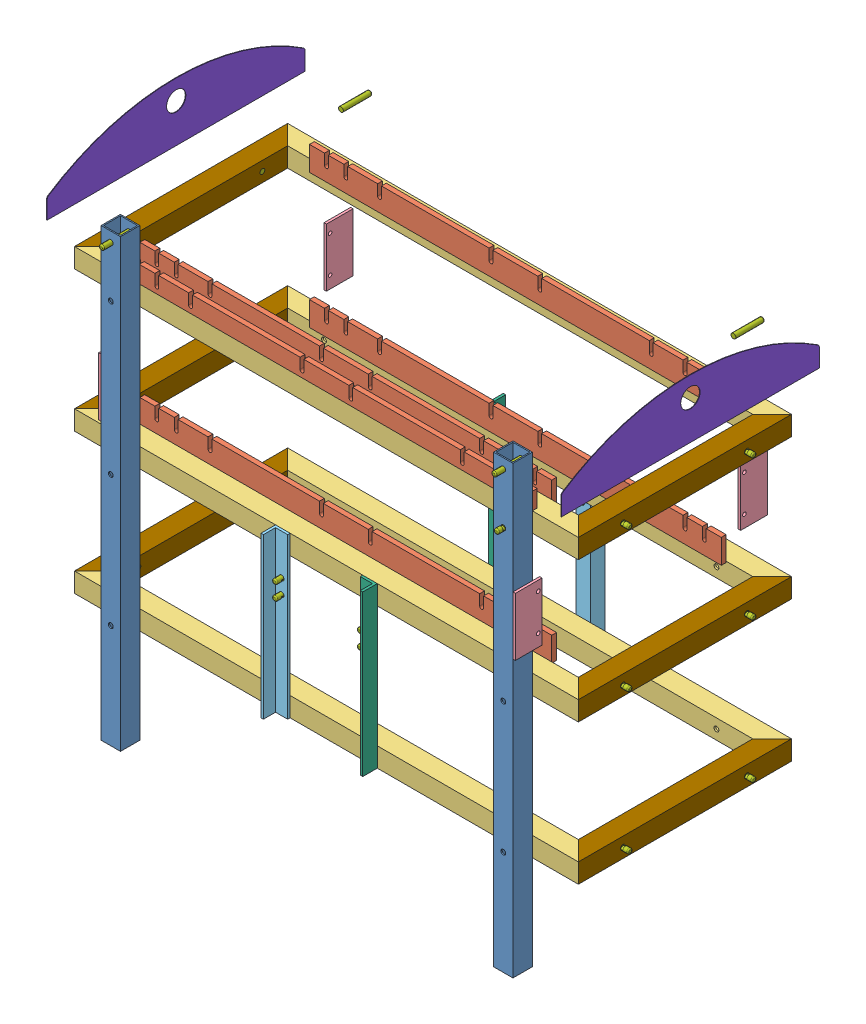
SolidWorks assembly 300-TableCage, configuration Default. Lengths in mm.
Overall size (1358.9 1271.5 704.85).
59 component instances, 12 part files, 76 mates.
Components (placement in the parent):
- 305-LegMain-1: 305-LegMain [Default] x (-1 0 0) z (0 1 0) size (50.8 50.8 1168.4)
- 307-HoldingBarRods-1: 307-HoldingBarRods [Default] at (0 0 279.4) x (-1 0 0) z (0 0 -1) size (1079.5 63.5 12.7)
- 309-TubingSquareTop-1: 309-TubingSquareTop [Default] x (0 0 -1) z (1 0 0) size (50.8 50.8 1320.8)
- 309-TubingSquareTop-2: 309-TubingSquareTop [Default] at (0 -368.3 0) x (0 0 -1) z (1 0 0) size (50.8 50.8 1320.8)
- 311-PlateYoke-1: 311-PlateYoke [Default] at (539.75 0 0) x (0 1 0) z (1 0 0) size (152.4 69.85 6.35)
- 309-TubingSquareTop-3: 309-TubingSquareTop [Default] at (0 -736.6 0) x (0 0 -1) z (1 0 0) size (50.8 50.8 1320.8)
- 308-AngleBracket-1: 308-AngleBracket [Default] at (851.05 400.05 9.525) x (0 0 -1) z (0 1 0) size (38.1 38.1 419.1)
- 308-AngleBracketMirror-1: 308-AngleBracketMirror [Default] at (-851.05 400.05 9.525) x (0 0 1) z (0 1 0) size (38.1 38.1 419.1)
- 321-DowellGrooved-1: 321-DowellGrooved [Default] at (851.05 400.05 279.4) x (0 -1 0) z (0 0 -1) size (12.7 12.7 25.4)
- 321-DowellGrooved-2: 321-DowellGrooved [Default] at (1073.3 400.05 279.4) x (0 -1 0) z (0 0 -1) size (12.7 12.7 25.4)
- 321-DowellGrooved-3: 321-DowellGrooved [Default] at (851.05 361.95 279.4) x (0 -1 0) z (0 0 -1) size (12.7 12.7 25.4)
- 321-DowellGrooved-4: 321-DowellGrooved [Default] at (1073.3 361.95 279.4) x (0 -1 0) z (0 0 -1) size (12.7 12.7 25.4)
- 400-LidUpper-1: 400-LidUpper [Default] at origin size (1349.2 153.62 676.1)
  - 401-Dome-1: 401-Dome [Default] x (0 0 -1) z (1 0 0) size (676.1 153.62 1346.2) (hidden)
  - 402-SideWall-1: 402-SideWall [Default] at (673.1 37.11 0) x (0 0 -1) z (1 0 0) size (676.1 153.62 1.5)
  - 402-SideWall-2: 402-SideWall [Default] at (-674.6 37.11 0) x (0 0 -1) z (1 0 0) size (676.1 153.62 1.5)
- 330-LexanSideShield-1: 330-LexanSideShield [Default] at (0 0 330.2) size (1330.33 882.65 4.76) (hidden)
- 304-BarUpper-1: 304-BarUpper [Default] at (-457.2 1473.2 -91.6) x (0 -1 0) z (0 0 1) size (50.8 50.8 558.8)
- 304-BarUpper-2: 304-BarUpper [Default] at (-457.2 1104.9 -91.6) x (0 -1 0) z (0 0 1) size (50.8 50.8 558.8)
- 304-BarUpper-3: 304-BarUpper [Default] at (-457.2 736.6 -91.6) x (0 -1 0) z (0 0 1) size (50.8 50.8 558.8)
- 321-DowellGrooved-5: 321-DowellGrooved [plain-long] at (-447.825 1202.1089 330.2) x (0 1 0) z (0 0 -1) size (12.7 12.7 76.2)
- 321-DowellGrooved-8: 321-DowellGrooved [long] at (654.05 1068.7589 1124.575) x (0 1 0) z (-1 0 0) size (12.7 12.7 69.85)
- 321-DowellGrooved-11: 321-DowellGrooved [long] at (654.05 1068.7589 799.775) x (0 1 0) z (-1 0 0) size (12.7 12.7 69.85)
- 321-DowellGrooved-13: 321-DowellGrooved [long] at (654.05 332.1589 799.775) x (0 1 0) z (-1 0 0) size (12.7 12.7 69.85)
- 321-DowellGrooved-10: 321-DowellGrooved [long] at (654.05 332.1589 1124.575) x (0 1 0) z (-1 0 0) size (12.7 12.7 69.85)
- 321-DowellGrooved-12: 321-DowellGrooved [long] at (654.05 700.4589 799.775) x (0 1 0) z (-1 0 0) size (12.7 12.7 69.85)
- 321-DowellGrooved-9: 321-DowellGrooved [long] at (654.05 700.4589 1124.575) x (0 1 0) z (-1 0 0) size (12.7 12.7 69.85)
- 331-LexanShield-1: 331-LexanShield [Default] at (660.4 1473.2 -91.6) x (0 1 0) z (1 0 0) size (882.65 654.05 4.76) (hidden)
- 305-LegMain-2: 305-LegMain [Default] at (0 0 609.6) x (1 0 0) z (0 1 0) size (50.8 50.8 1168.4)
- 311-PlateYoke-2: 311-PlateYoke [Default] at (-546.1 0 0) x (0 1 0) z (1 0 0) size (152.4 69.85 6.35)
- 304-BarUpper-4: 304-BarUpper [Default] at (457.2 1473.2 91.6) x (0 -1 0) z (0 0 -1) size (50.8 50.8 558.8)
- 304-BarUpper-5: 304-BarUpper [Default] at (457.2 1104.9 91.6) x (0 -1 0) z (0 0 -1) size (50.8 50.8 558.8)
- 304-BarUpper-6: 304-BarUpper [Default] at (457.2 736.6 91.6) x (0 -1 0) z (0 0 -1) size (50.8 50.8 558.8)
- 321-DowellGrooved-14: 321-DowellGrooved [plain-long] at (-1476.525 1202.1089 330.2) x (0 1 0) z (0 0 -1) size (12.7 12.7 76.2)
- 321-DowellGrooved-17: 321-DowellGrooved [long] at (-654.05 1068.7589 -799.775) x (0 1 0) z (1 0 0) size (12.7 12.7 69.85)
- 321-DowellGrooved-18: 321-DowellGrooved [long] at (-654.05 1068.7589 -1124.575) x (0 1 0) z (1 0 0) size (12.7 12.7 69.85)
- 321-DowellGrooved-19: 321-DowellGrooved [long] at (-654.05 332.1589 -1124.575) x (0 1 0) z (1 0 0) size (12.7 12.7 69.85)
- 321-DowellGrooved-20: 321-DowellGrooved [long] at (-654.05 332.1589 -799.775) x (0 1 0) z (1 0 0) size (12.7 12.7 69.85)
- 321-DowellGrooved-21: 321-DowellGrooved [long] at (-654.05 700.4589 -1124.575) x (0 1 0) z (1 0 0) size (12.7 12.7 69.85)
- 321-DowellGrooved-22: 321-DowellGrooved [long] at (-654.05 700.4589 -799.775) x (0 1 0) z (1 0 0) size (12.7 12.7 69.85)
- 331-LexanShield-2: 331-LexanShield [Default] at (-665.1625 1473.2 -91.6) x (0 1 0) z (1 0 0) size (882.65 654.05 4.76) (hidden)
- 309-TubingSquareTop-4: 309-TubingSquareTop [Default] x (0 0 1) z (-1 0 0) size (50.8 50.8 1320.8)
- 307-HoldingBarRods-4: 307-HoldingBarRods [Default] at (0 0 -215.9) x (-1 0 0) z (0 0 -1) size (1079.5 63.5 12.7)
- 309-TubingSquareTop-5: 309-TubingSquareTop [Default] at (0 -368.3 0) x (0 0 1) z (-1 0 0) size (50.8 50.8 1320.8)
- 311-PlateYoke-3: 311-PlateYoke [Default] at (546.1 0 0) x (0 1 0) z (-1 0 0) size (152.4 69.85 6.35)
- 309-TubingSquareTop-6: 309-TubingSquareTop [Default] at (0 -736.6 0) x (0 0 1) z (-1 0 0) size (50.8 50.8 1320.8)
- 308-AngleBracket-2: 308-AngleBracket [Default] at (-851.05 400.05 -9.525) x (0 0 1) z (0 1 0) size (38.1 38.1 419.1)
- 308-AngleBracketMirror-2: 308-AngleBracketMirror [Default] at (851.05 400.05 -9.525) x (0 0 -1) z (0 1 0) size (38.1 38.1 419.1)
- 321-DowellGrooved-23: 321-DowellGrooved [Default] at (-1073.3 400.05 -279.4) x (0 -1 0) z (0 0 1) size (12.7 12.7 25.4)
- 321-DowellGrooved-24: 321-DowellGrooved [Default] at (-851.05 400.05 -279.4) x (0 -1 0) z (0 0 1) size (12.7 12.7 25.4)
- 321-DowellGrooved-25: 321-DowellGrooved [Default] at (-1073.3 361.95 -279.4) x (0 -1 0) z (0 0 1) size (12.7 12.7 25.4)
- 321-DowellGrooved-26: 321-DowellGrooved [Default] at (-851.05 361.95 -279.4) x (0 -1 0) z (0 0 1) size (12.7 12.7 25.4)
- 321-DowellGrooved-27: 321-DowellGrooved [plain-long] at (1476.525 1202.1089 -323.85) x (0 1 0) z (0 0 1) size (12.7 12.7 76.2)
- 311-PlateYoke-4: 311-PlateYoke [Default] at (-539.75 0 0) x (0 1 0) z (-1 0 0) size (152.4 69.85 6.35)
- 321-DowellGrooved-30: 321-DowellGrooved [plain-long] at (447.825 1202.1089 -323.85) x (0 1 0) z (0 0 1) size (12.7 12.7 76.2)
- 321-DowellGrooved-31: 321-DowellGrooved [extralong] at (-447.825 1068.7589 323.85) x (0 1 0) z (0 0 -1) size (12.7 12.7 120.65)
- 307-HoldingBarRods-6: 307-HoldingBarRods [Default] at (0 -352.298 228.6) x (-1 0 0) z (0 0 -1) size (1079.5 63.5 12.7)
- 307-HoldingBarRods-7: 307-HoldingBarRods [Default] at (0 0 228.6) x (-1 0 0) z (0 0 -1) size (1079.5 63.5 12.7)
- 307-HoldingBarRods-8: 307-HoldingBarRods [Default] at (0 -352.298 -215.9) x (-1 0 0) z (0 0 -1) size (1079.5 63.5 12.7)
Mates (geometry in assembly coordinates):
- InPlace1: in place: plane of assembly; plane of 305-LegMain-1; moOrthogonalPlaneRef_w of assembly; plane of 305-LegMain-1; moOrthogonalPlaneRef_w of assembly; plane of 305-LegMain-1
- Coincident1: coincident: plane of 305-LegMain-1; plane of assembly
- Coincident2: coincident: plane of 305-LegMain-1; moOrthogonalPlaneRef_w of assembly
- Coincident3: coincident: plane of 305-LegMain-1; moOrthogonalPlaneRef_w of assembly
- InPlace3: in place: plane of 305-LegMain-1 through (539.75 -50.8 279.4) normal (0 0 -1); plane of 307-HoldingBarRods-1; moOrthogonalPlaneRef_w of 305-LegMain-1; plane of 307-HoldingBarRods-1; moOrthogonalPlaneRef_w of 305-LegMain-1; plane of 307-HoldingBarRods-1
- Coincident10: coincident aligned: plane of 305-LegMain-1; plane of 307-HoldingBarRods-1
- Coincident11: coincident aligned: moOrthogonalPlaneRef_w of 305-LegMain-1 through (0 0 279.4) axis (0 1 0); plane of 307-HoldingBarRods-1
- Coincident12: coincident anti-aligned: moOrthogonalPlaneRef_w of 305-LegMain-1 through (0 0 279.4) axis (1 0 0); plane of 307-HoldingBarRods-1 through (0 0 279.4) normal (-1 0 0)
- InPlace5: in place: unknown of ?
- Coincident47: coincident aligned: plane of 309-TubingSquareTop-1; plane of assembly
- Coincident48: coincident aligned: line of ? through (-726.44 0 0) axis (0 0 1)
- Coincident49: coincident anti-aligned: plane of ? through (0 0 0) normal (0 0 -1)
- InPlace6: in place: plane of 305-LegMain-1 through (539.75 -50.8 330.2) normal (1 0 0); plane of 311-PlateYoke-1; moOrthogonalPlaneRef_w of 305-LegMain-1; plane of 311-PlateYoke-1; moOrthogonalPlaneRef_w of 305-LegMain-1; plane of 311-PlateYoke-1
- Coincident53: coincident aligned: plane of 305-LegMain-1; plane of 311-PlateYoke-1
- Coincident54: coincident aligned: moOrthogonalPlaneRef_w of 305-LegMain-1 through (539.75 0 0) axis (0 0 1); plane of 311-PlateYoke-1
- Coincident55: coincident anti-aligned: moOrthogonalPlaneRef_w of 305-LegMain-1 through (-1000 539.75 0) axis (0 0 -1); plane of 311-PlateYoke-1
- Coincident58: coincident anti-aligned: plane of 309-TubingSquareTop-2 through (660.4 615.95 279.4) normal (0 0 1); plane of 308-AngleBracket-1 through (-95.25 669.8315 279.4) normal (0 0 -1)
- Distance2: distance = 127 mm aligned: plane of 308-AngleBracket-1 through (-127 669.8315 279.4) normal (1 0 0); plane of assembly through (0 0 0) normal (1 0 0)
- Coincident61: coincident aligned: plane of 308-AngleBracket-1 through (660.4 615.95 279.4) normal (0 1 0); plane of 308-AngleBracketMirror-1 through (-660.4 615.95 279.4) normal (0 1 0)
- Coincident62: coincident aligned: plane of 308-AngleBracket-1 through (-95.25 669.8315 285.75) normal (0 0 1); plane of 308-AngleBracketMirror-1 through (95.25 669.8315 285.75) normal (0 0 1)
- Distance3: distance = 254 mm anti-aligned: plane of 308-AngleBracket-1 through (-127 669.8315 279.4) normal (1 0 0); plane of 308-AngleBracketMirror-1 through (127 669.8315 279.4) normal (-1 0 0)
- InPlace7: in place: plane of 308-AngleBracket-1 through (-95.25 669.8315 279.4) normal (0 0 -1); plane of 321-DowellGrooved-1; moOrthogonalPlaneRef_w of 308-AngleBracket-1; plane of 321-DowellGrooved-1; moOrthogonalPlaneRef_w of 308-AngleBracket-1; plane of 321-DowellGrooved-1
- Coincident64: coincident aligned: plane of 308-AngleBracket-1; plane of 321-DowellGrooved-1
- Coincident65: coincident aligned: moOrthogonalPlaneRef_w of 308-AngleBracket-1 through (851.05 400.05 279.4) axis (-1 0 0); plane of 321-DowellGrooved-1
- Coincident66: coincident anti-aligned: moOrthogonalPlaneRef_w of 308-AngleBracket-1 through (851.05 400.05 279.4) axis (0 1 0); plane of 321-DowellGrooved-1
- Coincident78: coincident aligned: plane of 309-TubingSquareTop-1 through (660.4 984.25 279.4) normal (0 1 0); plane of 304-BarUpper-1 through (660.4 984.25 279.4) normal (0 1 0)
- Coincident79: coincident anti-aligned: plane of 309-TubingSquareTop-1 through (660.4 984.25 279.4) normal (0.707107 0 -0.707107); plane of 304-BarUpper-1 through (660.4 509.3393 279.4) normal (-0.707107 0 0.707107)
- Coincident80: coincident aligned: line of 309-TubingSquareTop-1 through (660.4 984.25 279.4) axis (0 -1 0); line of 304-BarUpper-1 through (660.4 984.25 279.4) axis (0 -1 0)
- Coincident81: coincident aligned: plane of 305-LegMain-1 through (539.75 -50.8 279.4) normal (0 0 -1); plane of 321-DowellGrooved-5 through (514.35 1092.2 279.4) normal (0 0 -1)
- Concentric2: concentric anti-aligned: cylinder of 305-LegMain-1 through (514.35 1092.2 279.4) axis (0 0 1) radius 6.35; cylinder of 321-DowellGrooved-5 through (514.35 1092.2 355.6) axis (0 0 -1) radius 6.35
- Parallel3: parallel aligned: plane of 321-DowellGrooved-5; plane of assembly through (0 0 0) normal (0 1 0)
- Concentric3: concentric anti-aligned: cylinder of 304-BarUpper-1 through (609.6 958.85 162.4) axis (1 0 0) radius 6.35; cylinder of 321-DowellGrooved-8 through (679.45 958.85 162.4) axis (-1 0 0) radius 6.35
- Coincident83: coincident aligned: plane of 304-BarUpper-1 through (609.6 984.25 279.4) normal (-1 0 0); plane of 321-DowellGrooved-8 through (609.6 958.85 162.4) normal (-1 0 0)
- Parallel4: parallel aligned: plane of 321-DowellGrooved-8; plane of assembly through (0 0 0) normal (0 1 0)
- Concentric4: concentric anti-aligned: cylinder of 304-BarUpper-1 through (609.6 958.85 -162.4) axis (1 0 0) radius 6.35; cylinder of 321-DowellGrooved-11 through (679.45 958.85 -162.4) axis (-1 0 0) radius 6.35
- Coincident85: coincident aligned: plane of 304-BarUpper-1 through (609.6 984.25 279.4) normal (-1 0 0); plane of 321-DowellGrooved-11 through (609.6 958.85 -162.4) normal (-1 0 0)
- InPlace12: in place: plane of 304-BarUpper-1 through (660.4 984.25 279.4) normal (1 0 0); plane of 331-LexanShield-1; moOrthogonalPlaneRef_w of 304-BarUpper-1; plane of 331-LexanShield-1; moOrthogonalPlaneRef_w of 304-BarUpper-1; plane of 331-LexanShield-1
- Coincident86: coincident aligned: plane of 304-BarUpper-1; plane of 331-LexanShield-1
- Coincident87: coincident aligned: moOrthogonalPlaneRef_w of 304-BarUpper-1 through (660.4 1473.2 -91.6) axis (0 0 1); plane of 331-LexanShield-1
- Coincident88: coincident anti-aligned: moOrthogonalPlaneRef_w of 304-BarUpper-1 through (660.4 1473.2 -91.6) axis (0 -1 0); plane of 331-LexanShield-1
- Coincident89: coincident aligned: plane of 308-AngleBracketMirror-1 through (-660.4 196.85 279.4) normal (0 -1 0); plane of 308-AngleBracket-2 through (-660.4 196.85 -279.4) normal (0 -1 0)
- Coincident90: coincident aligned: plane of 308-AngleBracketMirror-1 through (127 669.8315 279.4) normal (-1 0 0); plane of 308-AngleBracket-2 through (127 669.8315 -279.4) normal (-1 0 0)
- Coincident91: coincident aligned: plane of 308-AngleBracket-1 through (660.4 196.85 279.4) normal (0 -1 0); plane of 308-AngleBracketMirror-2 through (660.4 196.85 -279.4) normal (0 -1 0)
- Coincident92: coincident aligned: plane of 308-AngleBracket-1 through (-133.35 669.8315 279.4) normal (-1 0 0); plane of 308-AngleBracketMirror-2 through (-133.35 669.8315 -279.4) normal (-1 0 0)
- Coincident93: coincident aligned: plane of 308-AngleBracket-2 through (95.25 669.8315 -279.4) normal (0 0 1); plane of 308-AngleBracketMirror-2 through (-95.25 669.8315 -279.4) normal (0 0 1)
- Distance4: distance = 279.4 mm aligned: plane of 308-AngleBracket-2 through (95.25 669.8315 -279.4) normal (0 0 1); plane of assembly through (0 0 0) normal (0 0 1)
- Coincident94: coincident: plane of 309-TubingSquareTop-2 through (660.4 615.95 279.4) normal (0 1 0); plane of 309-TubingSquareTop-5 through (-660.4 615.95 -279.4) normal (0 1 0)
- Coincident96: coincident aligned: plane of 308-AngleBracketMirror-1 through (-660.4 615.95 279.4) normal (0 1 0); plane of 308-AngleBracket-2 through (-660.4 615.95 -279.4) normal (0 1 0)
- Coincident97: coincident aligned: plane of 309-TubingSquareTop-2 through (660.4 615.95 279.4) normal (0 1 0); plane of 304-BarUpper-5 through (-660.4 615.95 -279.4) normal (0 1 0)
- Concentric7: concentric aligned: cylinder of 305-LegMain-2 through (-514.35 1092.2 330.2) axis (0 0 -1) radius 6.35; cylinder of 321-DowellGrooved-14 through (-514.35 1092.2 355.6) axis (0 0 -1) radius 6.35
- Concentric14: concentric anti-aligned: cylinder of 304-BarUpper-6 through (-609.6 222.25 162.4) axis (-1 0 0) radius 6.35; cylinder of 321-DowellGrooved-20 through (-679.45 222.25 162.4) axis (1 0 0) radius 6.35
- Concentric15: concentric anti-aligned: cylinder of 304-BarUpper-6 through (-609.6 222.25 -162.4) axis (-1 0 0) radius 6.35; cylinder of 321-DowellGrooved-19 through (-679.45 222.25 -162.4) axis (1 0 0) radius 6.35
- Concentric16: concentric anti-aligned: cylinder of 304-BarUpper-4 through (-609.6 958.85 162.4) axis (-1 0 0) radius 6.35; cylinder of 321-DowellGrooved-17 through (-679.45 958.85 162.4) axis (1 0 0) radius 6.35
- Concentric17: concentric anti-aligned: cylinder of 304-BarUpper-4 through (-609.6 958.85 -162.4) axis (-1 0 0) radius 6.35; cylinder of 321-DowellGrooved-18 through (-679.45 958.85 -162.4) axis (1 0 0) radius 6.35
- Concentric18: concentric anti-aligned: cylinder of 308-AngleBracket-2 through (111.125 509.9589 -279.4) axis (0 0 -1) radius 6.35; cylinder of 321-DowellGrooved-24 through (111.125 509.9589 -304.8) axis (0 0 1) radius 6.35
- Concentric19: concentric anti-aligned: cylinder of 308-AngleBracket-2 through (111.125 471.8589 -279.4) axis (0 0 -1) radius 6.35; cylinder of 321-DowellGrooved-26 through (111.125 471.8589 -304.8) axis (0 0 1) radius 6.35
- Concentric20: concentric anti-aligned: cylinder of 308-AngleBracketMirror-2 through (-111.125 509.9589 -279.4) axis (0 0 -1) radius 6.35; cylinder of 321-DowellGrooved-23 through (-111.125 509.9589 -304.8) axis (0 0 1) radius 6.35
- Concentric21: concentric anti-aligned: cylinder of 308-AngleBracketMirror-2 through (-111.125 471.8589 -279.4) axis (0 0 -1) radius 6.35; cylinder of 321-DowellGrooved-25 through (-111.125 471.8589 -304.8) axis (0 0 1) radius 6.35
- Coincident98: coincident aligned: plane of 305-LegMain-2 through (-539.75 -50.8 279.4) normal (0 0 -1); plane of 321-DowellGrooved-14 through (-514.35 1092.2 279.4) normal (0 0 -1)
- Concentric22: concentric anti-aligned: cylinder of 309-TubingSquareTop-1 through (514.35 958.85 228.6) axis (0 0 1) radius 6.35; cylinder of 321-DowellGrooved-31 through (514.35 958.85 349.25) axis (0 0 -1) radius 6.35
- Coincident100: coincident aligned: plane of 309-TubingSquareTop-1 through (660.4 984.25 228.6) normal (0 0 -1); plane of 321-DowellGrooved-31 through (514.35 958.85 228.6) normal (0 0 -1)
- Parallel5: parallel aligned: plane of 321-DowellGrooved-31; plane of assembly through (0 0 0) normal (0 1 0)
- Coincident101: coincident anti-aligned: plane of 309-TubingSquareTop-1 through (660.4 984.25 228.6) normal (0 0 -1); plane of 307-HoldingBarRods-7 through (539.75 965.2 228.6) normal (0 0 1)
- Coincident102: coincident aligned: plane of 307-HoldingBarRods-1 through (539.75 1028.7 266.7) normal (1 0 0); plane of 307-HoldingBarRods-7 through (539.75 1028.7 215.9) normal (1 0 0)
- Coincident103: coincident aligned: plane of 307-HoldingBarRods-1 through (539.75 1028.7 266.7) normal (0 1 0); plane of 307-HoldingBarRods-7 through (539.75 1028.7 215.9) normal (0 1 0)
- Coincident104: coincident anti-aligned: plane of 309-TubingSquareTop-2 through (660.4 615.95 228.6) normal (0 0 -1); plane of 307-HoldingBarRods-6 through (539.75 612.902 228.6) normal (0 0 1)
- Coincident109: coincident aligned: plane of 307-HoldingBarRods-4 through (539.75 1028.7 -228.6) normal (1 0 0); plane of 307-HoldingBarRods-7 through (539.75 1028.7 215.9) normal (1 0 0)
- Coincident113: coincident aligned: plane of 309-TubingSquareTop-2 through (660.4 615.95 279.4) normal (0 1 0); plane of 304-BarUpper-2 through (660.4 615.95 279.4) normal (0 1 0)
- Coincident114: coincident anti-aligned: plane of 309-TubingSquareTop-3 through (660.4 247.65 279.4) normal (0 0 1); plane of 308-AngleBracketMirror-1 through (95.25 669.8315 279.4) normal (0 0 -1)
- Coincident115: coincident aligned: plane of 309-TubingSquareTop-3 through (660.4 196.85 279.4) normal (0 -1 0); plane of 308-AngleBracket-1 through (660.4 196.85 279.4) normal (0 -1 0)
- Distance7: distance = 368.3 mm: plane of 309-TubingSquareTop-1 through (660.4 984.25 279.4) normal (0 1 0); plane of 309-TubingSquareTop-2 through (660.4 615.95 279.4) normal (0 1 0)
- Distance8: distance = 431.8 mm anti-aligned: plane of 307-HoldingBarRods-7 through (539.75 965.2 215.9) normal (0 0 -1); plane of 307-HoldingBarRods-4 through (539.75 965.2 -215.9) normal (0 0 1)
- Coincident123: coincident anti-aligned: plane of 309-TubingSquareTop-5 through (-660.4 615.95 -228.6) normal (0 0 1); plane of 307-HoldingBarRods-8 through (539.75 612.902 -228.6) normal (0 0 -1)
- Coincident125: coincident aligned: plane of 307-HoldingBarRods-4 through (539.75 1028.7 -228.6) normal (1 0 0); plane of 307-HoldingBarRods-8 through (539.75 676.402 -228.6) normal (1 0 0)
- Distance11: distance = 47.752 mm aligned: plane of 307-HoldingBarRods-8 through (539.75 612.902 -228.6) normal (0 -1 0); plane of 309-TubingSquareTop-5 through (-660.4 565.15 -279.4) normal (0 -1 0)
- Coincident128: coincident: plane of 307-HoldingBarRods-6 through (539.75 612.902 215.9) normal (0 -1 0); plane of 307-HoldingBarRods-8 through (539.75 612.902 -228.6) normal (0 -1 0)
